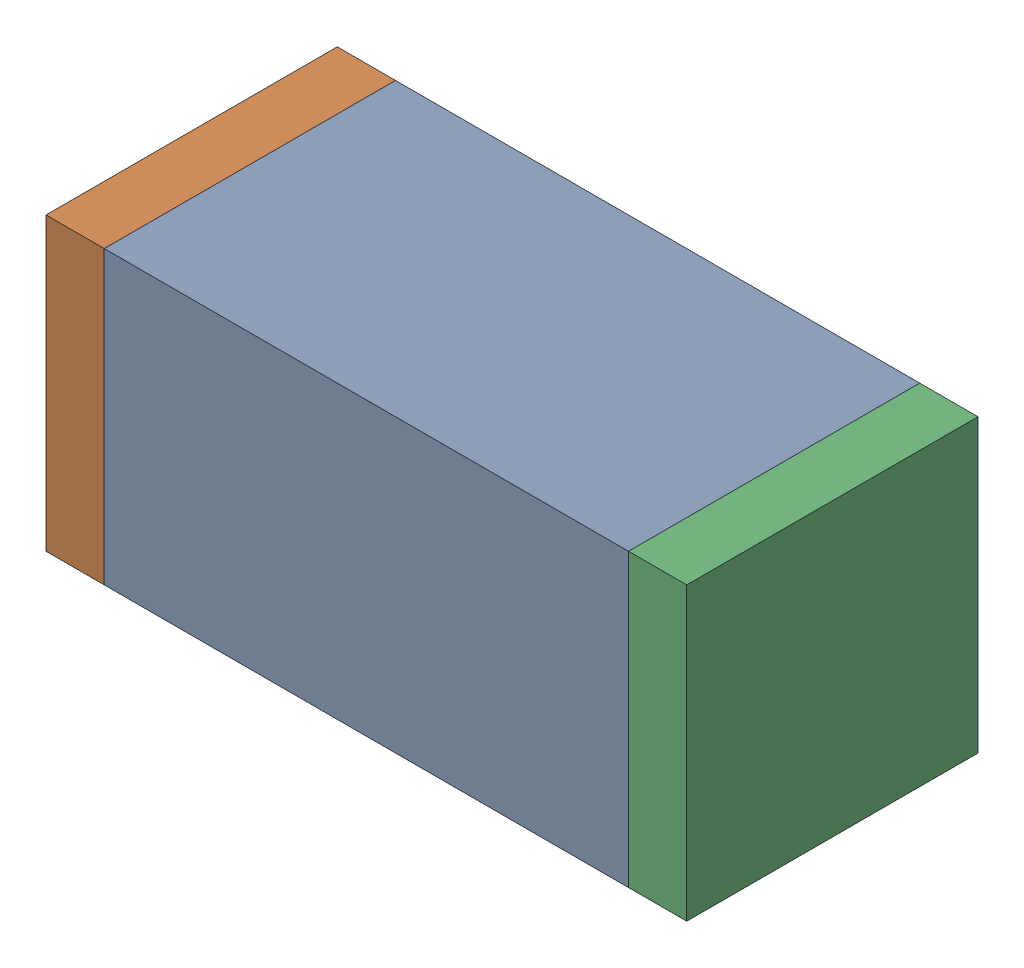
SolidWorks assembly C106, configuration Default. Lengths in mm.
Overall size (1.1 0.5 0.5).
6 component instances, 2 part files, 0 mates.
Components (placement in the parent):
- 836749680-1: 836749680 [Default] at (111.4 75.45 0) size (0.9 0.5 0.5)
  - Extruded_4-1: Extruded_4 [Default] at origin size (0.9 0.5 0.5)
- 810156080-1: 810156080 [Default] at (110.9 75.45 0) size (0.1 0.5 0.5)
  - Extruded_5-1: Extruded_5 [Default] at origin size (0.1 0.5 0.5)
- 810156080-2: 810156080 [Default] at (111.9 75.45 0) size (0.1 0.5 0.5)
  - Extruded_5-1: Extruded_5 [Default] at origin size (0.1 0.5 0.5)
